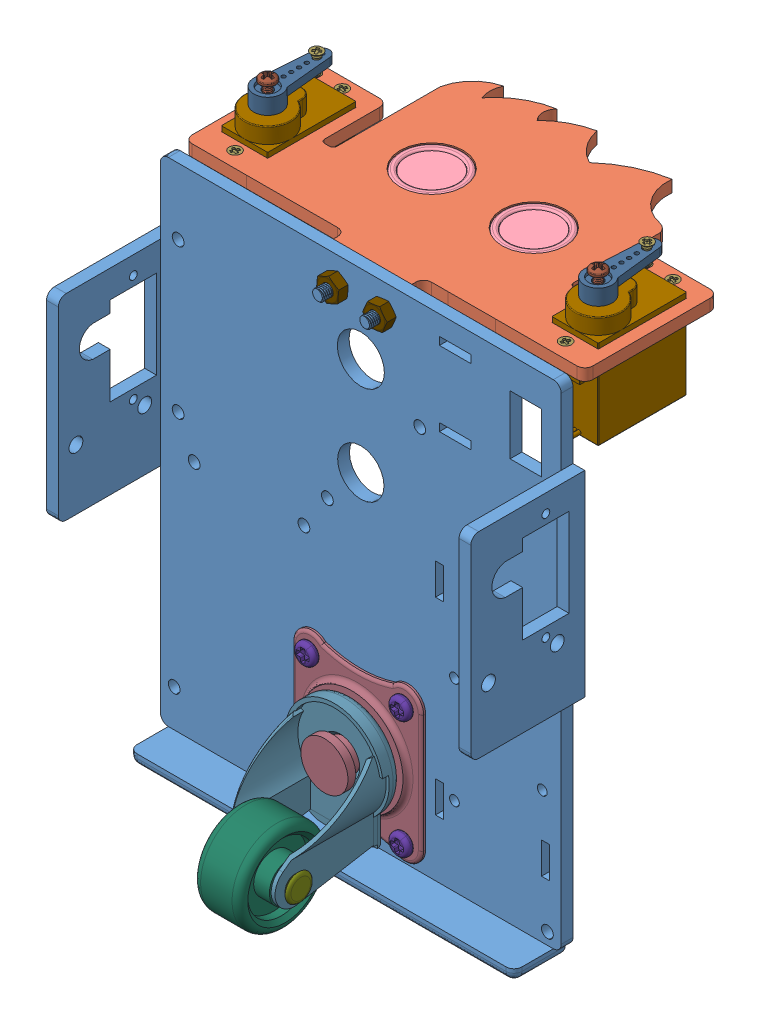
SolidWorks assembly DYOR_3D_AC, configuration Predeterminado. Lengths in mm.
Overall size (108 144.05 98.01).
48 component instances, 19 part files, 18 mates.
Components (placement in the parent):
- Base-1: Base [Predeterminado] at (60.418 -80.9125 12.5389) size (108 128.45 29)
- Front_AC-1: Front_AC [Predeterminado] at (-51.2809 39.5388 -46.5191) x (1 0 0) z (0 1 0) size (101.94 57.42 11)
- HC-SR04 Ping Sensor-1: HC-SR04 Ping Sensor [Default] at (9.418 28.7888 -18.4981) x (0 0 -1) z (0 1 0) size (25.18 45 18.07)
  - PCB-1: PCB [Default] at origin size (20.5 45 1.75)
  - Transducer-1: Transducer [Default] at (0 -13 13.25) x (1 0 0) z (0 -1 0) size (15.88 12 15.88)
  - Transducer-2: Transducer [Default] at (0 13 13.25) x (1 0 0) z (0 -1 0) size (15.88 12 15.88)
  - 3 Pin Header 90 Degree-1: 3 Pin Header 90 Degree [Default] at (8.4275 0 -1.25) x (-1 0 0) z (0 -1 0) size (8 7.82 10)
  - 14 Pin SMT-1: 14 Pin SMT [Default] at (-0.35 -18.5 -0.85) x (0 -1 0) z (1 0 0) size (6 1.6 8.8)
  - 14 Pin SMT-2: 14 Pin SMT [Default] at (0 -0.3826 -0.85) x (1 0 0) z (0 1 0) size (6 1.6 8.8)
  - 14 Pin SMT-3: 14 Pin SMT [Default] at (0 17.5274 -0.85) x (1 0 0) z (0 1 0) size (6 1.6 8.8)
  - Cap1 SMT-1: Cap1 SMT [Default] at (-1.755 7.4774 -0.9689) x (0 1 0) z (-1 0 0) size (4.5 1.84 1.75)
  - Cap1 SMT-2: Cap1 SMT [Default] at (6.835 7.4774 -0.9689) x (0 1 0) z (-1 0 0) size (4.5 1.84 1.75)
  - Cap1 SMT-3: Cap1 SMT [Default] at (-6.835 7.4774 -0.9689) x (0 1 0) z (-1 0 0) size (4.5 1.84 1.75)
  - Cap1 SMT-4: Cap1 SMT [Default] at (4.295 7.4774 -0.9689) x (0 1 0) z (-1 0 0) size (4.5 1.84 1.75)
  - Cap1 SMT-5: Cap1 SMT [Default] at (1.755 7.4774 -0.9689) x (0 1 0) z (-1 0 0) size (4.5 1.84 1.75)
  - Cap1 SMT-6: Cap1 SMT [Default] at (-4.295 7.4774 -0.9689) x (0 1 0) z (-1 0 0) size (4.5 1.84 1.75)
  - HC-SR04 Crystal-1: HC-SR04 Crystal [Default] at (-8.3 0 1.75) x (0 -1 0) z (0 0 1) size (10 3.5 2.7)
- AC-1: AC [Predeterminado] at (-137.3228 216.8523 -134.1762) size (95.94 34.06 31.9)
  - sg90-1: sg90 [Default] at (182.9409 -195.7135 134.2781) x (0 0 -1) z (1 0 0) size (31.9 29.9 11.8)
  - sg90-2: sg90 [Default] at (98.7972 -195.7135 134.2781) x (0 0 -1) z (1 0 0) size (31.9 29.9 11.8)
  - SG90 plastic Horn-1: SG90 plastic Horn [Default] at (188.8409 -166.2635 128.3781) x (-0.029359 0 -0.999569) z (0.999569 0 -0.029359) size (19.4 4 7.07)
  - SG90 plastic Horn-2: SG90 plastic Horn [Default] at (104.6972 -166.2635 128.3781) x (-0.012387 0 -0.999923) z (0.999923 0 -0.012387) size (19.4 4 7.07)
  - (M2_3_mm)_90116A007_METRIC 316 SS PAN HEAD PHILLIPS MACHINE SCREW-1: (M2_3_mm)_90116A007_METRIC 316 SS PAN HEAD PHILLIPS MACHINE SCREW [90116A007] at (104.6972 -166.2635 128.3781) x (-1 0 0) z (0 1 0) size (4 4 4.68)
  - (M2_3_mm)_90116A007_METRIC 316 SS PAN HEAD PHILLIPS MACHINE SCREW-2: (M2_3_mm)_90116A007_METRIC 316 SS PAN HEAD PHILLIPS MACHINE SCREW [90116A007] at (188.8409 -166.2635 128.3781) x (-1 0 0) z (0 1 0) size (4 4 4.68)
  - M2x6 SelfTap Screw-1: M2x6 SelfTap Screw [Predeterminado] at (104.6972 -162.7635 115.8781) x (0.825172 0 -0.564882) z (0 1 0) size (3.4 3.28 6)
  - M2x6 SelfTap Screw-2: M2x6 SelfTap Screw [Predeterminado] at (188.7787 -162.7635 115.8783) x (0.001298 0 -0.999999) z (0 1 0) size (3.4 3.28 6)
  - M2x6 SelfTap Screw-3: M2x6 SelfTap Screw [Predeterminado] at (104.6972 -174.3135 109.3781) x (-0.923728 0 -0.383049) z (0 1 0) size (3.4 3.28 6)
  - M2x6 SelfTap Screw-4: M2x6 SelfTap Screw [Predeterminado] at (104.6972 -174.3135 136.6781) x (-0.923728 0 -0.383049) z (0 1 0) size (3.4 3.28 6)
  - M2x6 SelfTap Screw-5: M2x6 SelfTap Screw [Predeterminado] at (188.8409 -174.3135 136.6781) x (0.923728 0 0.383049) z (0 1 0) size (3.4 3.28 6)
  - M2x6 SelfTap Screw-6: M2x6 SelfTap Screw [Predeterminado] at (188.8409 -174.3135 109.3781) x (0.923728 0 0.383049) z (0 1 0) size (3.4 3.28 6)
- CA-1: CA [Predeterminado] at (-2.207 18.0036 0) size (33 45.94 43.2)
  - Caster Wheel-1: Caster Wheel [Default] at (57.6387 -78.841 57.7572) x (0 1 0) z (-1 0 0) size (45.94 37.59 33)
    - caster holder-1: caster holder [Default] at (-24.0751 44.7184 29.5137) x (1 0 0) z (0 0 -1) size (39 9.27 33)
    - holder-1: holder [Default] at (-1.5751 42.9484 46.0137) x (0 0 1) z (1 0 0) size (25 28.07 31.31)
    - caster wheel-1: caster wheel [Default] at (-15.6961 19.9484 46.0137) x (0.997275 0.073773 0) z (0 0 1) size (23 23 14)
    - Part4-1: Part4 [Default] at (-15.6961 19.9484 55.0137) x (-0.978448 0.206495 0) z (0 0 -1) size (7 7 20)
  - M3x6 Philips Screw-1: M3x6 Philips Screw [Predeterminado] at (23.625 -65.4161 13.5389) size (5.3 5.3 7.81)
  - M3x6 Philips Screw-2: M3x6 Philips Screw [Predeterminado] at (-0.375 -65.4161 13.5389) size (5.3 5.3 7.81)
  - M3x6 Philips Screw-3: M3x6 Philips Screw [Predeterminado] at (-0.375 -95.4161 13.5389) size (5.3 5.3 7.81)
  - M3x6 Philips Screw-4: M3x6 Philips Screw [Predeterminado] at (23.625 -95.4161 13.5389) size (5.3 5.3 7.81)
  - M3 Nut-1: M3 Nut [Predeterminado] at (23.625 -65.4161 11.0389) size (6.27 6.27 2.71)
  - M3 Nut-2: M3 Nut [Predeterminado] at (-0.375 -65.4161 11.0389) size (6.27 6.27 2.71)
  - M3 Nut-3: M3 Nut [Predeterminado] at (-0.375 -95.4161 11.0389) size (6.27 6.27 2.71)
  - M3 Nut-4: M3 Nut [Predeterminado] at (23.625 -95.4161 11.0389) size (6.27 6.27 2.71)
- M3 Nut-1: M3 Nut [Predeterminado] at (15.418 36.0388 16.5389) x (0.795083 0.6065 0) z (0 0 1) size (6.27 6.27 2.71)
- M3 Nut-2: M3 Nut [Predeterminado] at (3.418 36.0388 16.5389) x (0.997165 -0.07525 0) z (0 0 1) size (6.27 6.27 2.71)
- M3x10 Philips Screw-1: M3x10 Philips Screw [Predeterminado] at (15.418 36.0388 7.5389) x (-0.923728 -0.383049 0) z (0 0 -1) size (5.3 5.3 11.8)
- M3x10 Philips Screw-2: M3x10 Philips Screw [Predeterminado] at (3.418 36.0388 7.5389) x (-0.923728 -0.383049 0) z (0 0 -1) size (5.3 5.3 11.8)
Mates (geometry in assembly coordinates):
- Coincidente15: coincident: plane of Base-1 through (-39.582 40.5388 9.5389) normal (0 0 -1); plane of Front_AC-1 through (19.418 42.5388 9.5389) normal (0 0 1)
- Concéntrica11: concentric: circle of Front_AC-1; circle of HC-SR04 Ping Sensor-1/Transducer-1
- Concéntrica12: concentric: circle of Front_AC-1; circle of HC-SR04 Ping Sensor-1/Transducer-2
- Coincidente16: coincident: plane of Front_AC-1 through (-2.582 42.5388 8.4425) normal (0 1 0); plane of HC-SR04 Ping Sensor-1/Transducer-2 through (-3.582 42.5388 -26.4381) normal (0 1 0)
- Coincidente22: coincident: plane of Front_AC-1 through (45.618 42.5388 -22.3981) normal (1 0 0); plane of AC-1/sg90-1 through (45.618 21.1388 0.1019) normal (-1 0 0)
- Coincidente23: coincident: plane of Front_AC-1 through (57.418 42.5388 -22.3981) normal (0 0 1); plane of AC-1/sg90-1 through (57.418 21.1388 -22.3981) normal (0 0 -1)
- Coincidente24: coincident: plane of Front_AC-1 through (-2.582 39.5388 8.4425) normal (0 -1 0); plane of AC-1/sg90-1 through (57.418 39.5388 -27.0981) normal (0 1 0)
- Coincidente25: coincident: plane of Base-1 through (-39.582 40.5388 12.5389) normal (0 0 1); plane of CA-1/Caster Wheel-1/caster holder-1 through (9.418 -17.6143 12.5389) normal (0 0 -1)
- Concéntrica15: concentric: circle of Base-1; circle of CA-1/M3x6 Philips Screw-1
- Concéntrica16: concentric: circle of Base-1; circle of CA-1/M3x6 Philips Screw-4
- Coincidente31: coincident: plane of Front_AC-1 through (3.418 36.0388 7.5389) normal (0 0 -1); plane of M3x10 Philips Screw-2 through (2.8052 37.5167 7.5389) normal (0 0 1)
- Concéntrica21: concentric: circle of Front_AC-1; circle of M3x10 Philips Screw-2
- Coincidente32: coincident: plane of Front_AC-1 through (15.418 36.0388 7.5389) normal (0 0 -1); plane of M3x10 Philips Screw-1 through (14.8052 37.5167 7.5389) normal (0 0 1)
- Concéntrica22: concentric: circle of Front_AC-1; circle of M3x10 Philips Screw-1
- Concéntrica23: concentric: circle of Base-1; circle of M3 Nut-1
- Concéntrica24: concentric: circle of Base-1; circle of M3 Nut-2
- Coincidente36: coincident: plane of Base-1 through (-39.582 40.5388 12.5389) normal (0 0 1); plane of M3 Nut-1 through (15.418 36.0388 12.5389) normal (0 0 -1)
- Coincidente37: coincident: plane of Base-1 through (-39.582 40.5388 12.5389) normal (0 0 1); plane of M3 Nut-2 through (3.418 36.0388 12.5389) normal (0 0 -1)
